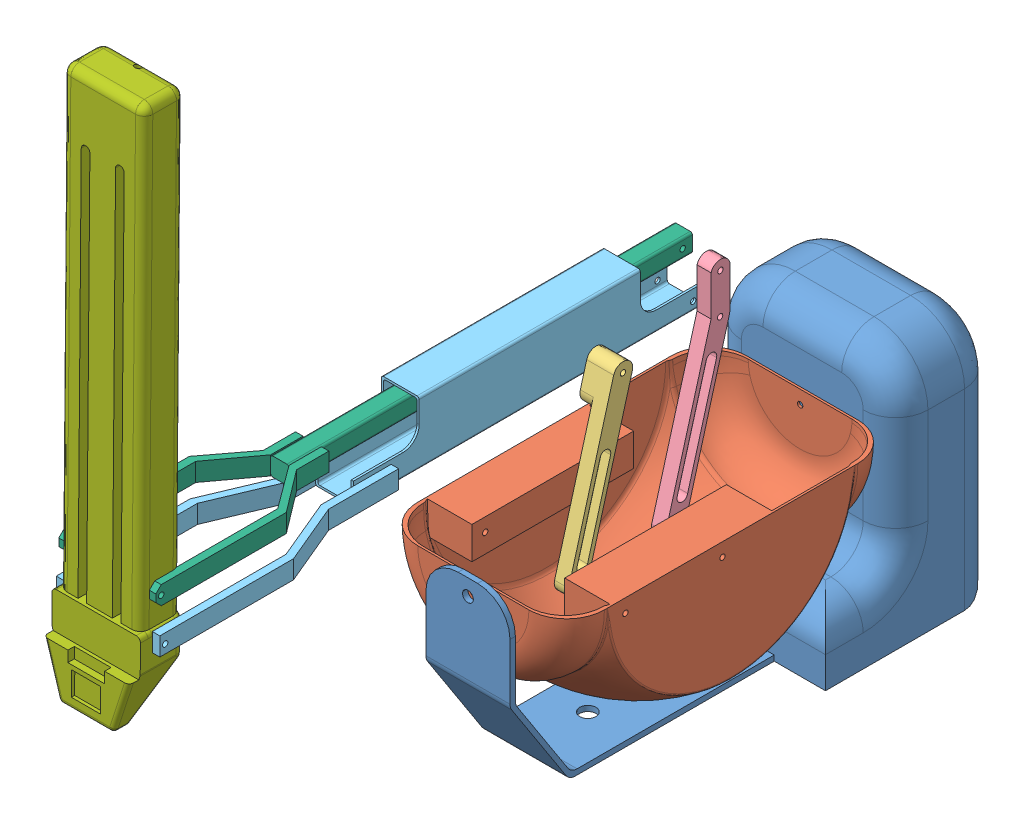
SolidWorks assembly ActiveSection, configuration Default. Lengths in mm.
Overall size (173.42 734.4 758.3).
7 component instances, 7 part files, 15 mates.
Components (placement in the parent):
- L1-1: L1 [Default] at (-68.7537 -23.5534 169.1519) size (173 228 404)
- L2-1: L2 [Default] at (-29.7537 67.7343 50.5284) size (173.42 143 305)
- LP12-1: LP12 [Default] at (-0.2537 151.1135 121.8589) x (0 -0.267998 -0.963419) z (1 0 0) size (18 173.91 25)
- LP11-1: LP11 [Default] at (-0.2537 95.7196 44.9923) x (0 -0.269759 -0.962928) z (1 0 0) size (27.97 209.62 13)
- LP21-1: LP21 [Default] at (-27.3141 259.523 7.7454) size (96 58 534)
- LP22-1: LP22 [Default] at (0.8884 224.0342 7.4385) size (90 17 534)
- L3-2: L3 [Default] at (-26.1906 634.2205 507.9112) x (1 0 0) z (0 -0.999966 0.008294) size (82 50 500)
Mates (geometry in assembly coordinates):
- Coincident1: coincident anti-aligned: plane of L1-1 through (9.2463 70.2343 203.0301) normal (0 0 -1); plane of L2-1 through (-29.7537 67.7343 203.0301) normal (0 0 1)
- Concentric1: concentric aligned: cylinder of L1-1 through (-29.7537 55.2343 -195.9699) axis (0 0 1) radius 5; circle of L2-1
- Coincident2: coincident anti-aligned: plane of L2-1 through (12.7463 37.7343 160.8722) normal (-1 0 0); plane of LP12-1 through (12.7463 205.4449 106.7454) normal (1 0 0)
- Concentric2: concentric anti-aligned: cylinder of L2-1 through (-116.4646 55.2343 148.5301) axis (1 0 0) radius 2.5; cylinder of LP12-1 through (12.7463 55.2343 148.5301) axis (-1 0 0) radius 2.5
- Coincident3: coincident anti-aligned: plane of LP12-1 through (-12.2537 205.4449 106.7454) normal (-1 0 0); plane of LP21-1 through (-12.2537 253.4449 331.7454) normal (1 0 0)
- Concentric3: concentric anti-aligned: cylinder of LP12-1 through (12.7463 205.4449 106.7454) axis (-1 0 0) radius 2.5; cylinder of LP21-1 through (-47.2537 205.4449 106.7454) axis (1 0 0) radius 2.5
- Coincident4: coincident anti-aligned: plane of L2-1 through (12.7463 37.7343 160.8722) normal (-1 0 0); plane of LP11-1 through (12.7463 242.4436 16.4385) normal (1 0 0)
- Concentric4: concentric anti-aligned: cylinder of L2-1 through (-116.4646 55.2343 58.5301) axis (1 0 0) radius 2.5; cylinder of LP11-1 through (12.7463 55.2343 58.5301) axis (-1 0 0) radius 2.5
- Concentric5: concentric anti-aligned: cylinder of LP11-1 through (12.7463 205.4449 16.7454) axis (-1 0 0) radius 2.5; cylinder of LP21-1 through (-47.2537 205.4449 16.7454) axis (1 0 0) radius 2.5
- Concentric6: concentric anti-aligned: cylinder of LP11-1 through (12.7463 242.4436 16.4385) axis (-1 0 0) radius 2.5; cylinder of LP22-1 through (-75.7537 242.4436 16.4385) axis (1 0 0) radius 2.5
- Distance1: distance = 8 mm anti-aligned: plane of LP22-1 through (-22.2537 248.9436 381.4385) normal (1 0 0); plane of LP21-1 through (-14.2537 251.4449 331.7454) normal (-1 0 0)
- Concentric10: concentric aligned: cylinder of LP22-1 through (-75.7537 242.4436 536.4385) axis (1 0 0) radius 2.5; cylinder of L3-2 through (-70.7537 242.4436 536.4385) axis (1 0 0) radius 2.5
- Concentric11: concentric aligned: cylinder of LP21-1 through (-77.7537 205.4449 536.7454) axis (1 0 0) radius 2.5; cylinder of L3-2 through (-70.7537 205.4449 536.7454) axis (1 0 0) radius 2.5
- Coincident8: coincident anti-aligned: plane of LP21-1 through (-70.7537 214.4449 541.7454) normal (1 0 0); plane of L3-2 through (-70.7537 134.24 512.3351) normal (-1 0 0)
- Parallel1: parallel aligned: plane of L1-1 through (6.7463 78.2343 -195.9699) normal (0 0 -1); plane of LP11-1 through (12.7463 206.1387 7.7721) normal (0 0 -1)
